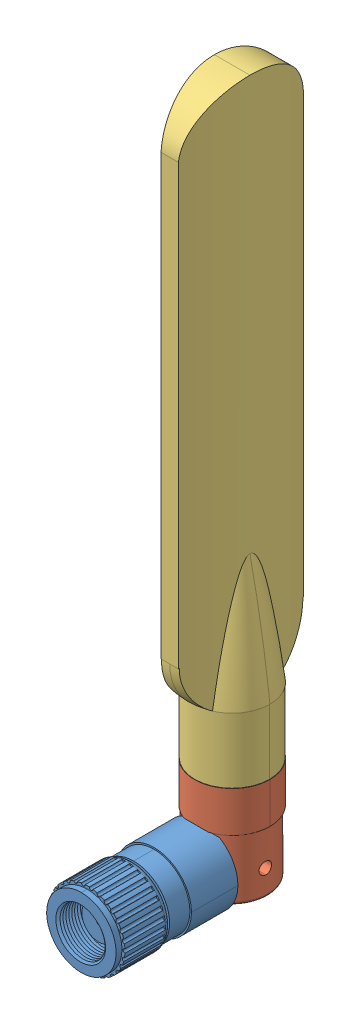
SolidWorks assembly WiFi Antenna.STEP, configuration Default. Lengths in mm.
Overall size (13.11 123.54 37.14).
3 component instances, 3 part files, 0 mates.
Components (placement in the parent):
- Antenna bottom.STEP-1: Antenna bottom.STEP [Default] x (0 -1 0) z (0 0 1) size (13.16 13.11 28.81)
- Antenna center.STEP-1: Antenna center.STEP [Default] at (-0.0003 15.5011 -25.9597) x (1 0 0) z (0 -1 0) size (13 13 17.61)
- Antenna.STEP-1: Antenna.STEP [Default] at (-0.0003 17.4531 -25.9597) x (0 0 -1) z (1 0 0) size (21.77 103.86 13.02)
